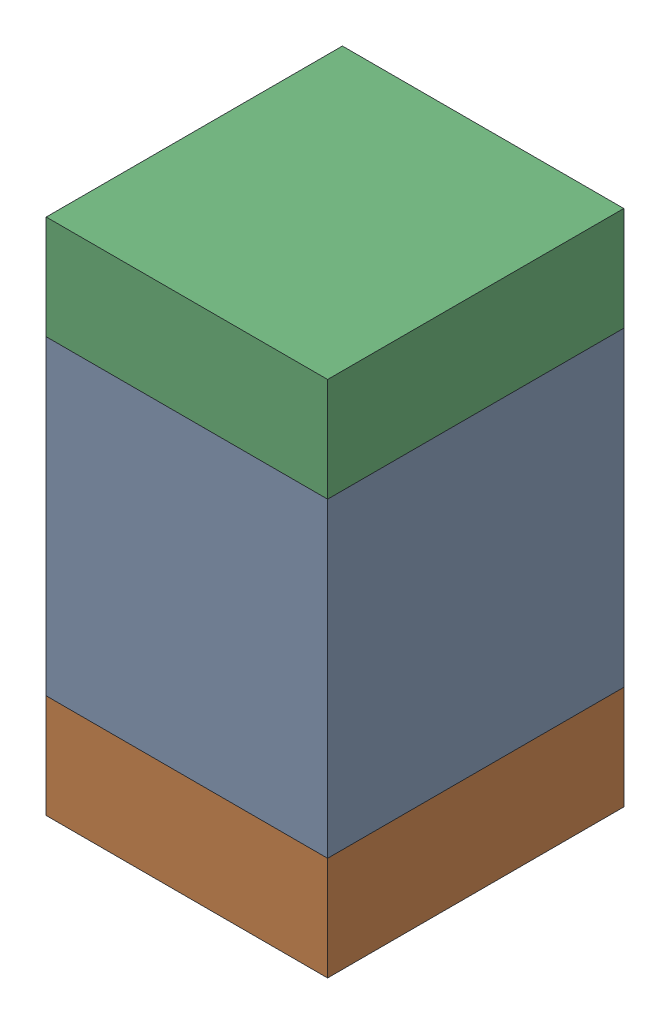
SolidWorks assembly C7-2, configuration Default. Lengths in mm.
Overall size (0.95 1.75 1).
6 component instances, 2 part files, 0 mates.
Components (placement in the parent):
- 959208528-2-1: 959208528-2 [Default] at (145.288 83.8282 0) size (0.95 1.05 1)
  - Extruded-77-1: Extruded-77 [Default] at origin size (0.95 1.05 1)
- 959208664-2-1: 959208664-2 [Default] at (145.288 83.1282 0) size (0.95 0.35 1)
  - Extruded-76-1: Extruded-76 [Default] at origin size (0.95 0.35 1)
- 959208664-2-2: 959208664-2 [Default] at (145.288 84.5282 0) size (0.95 0.35 1)
  - Extruded-76-1: Extruded-76 [Default] at origin size (0.95 0.35 1)
